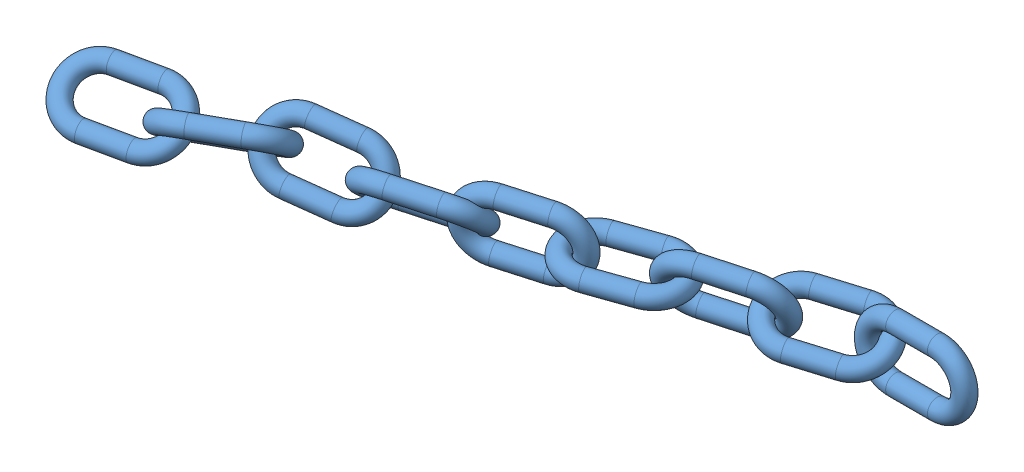
SolidWorks assembly chaine maillons soudés dia 6 L24 l 11, configuration Défaut. Lengths in mm.
Overall size (213.96 40.16 99.68).
9 component instances, 1 part files, 8 mates.
Components (placement in the parent):
- maillons chaine courte soudes dia 6 L 24 l 11-1: maillons chaine courte soudes dia 6 L 24 l 11 [Défaut] at (-85.1355 11.4536 0) size (36 23 6)
- maillons chaine courte soudes dia 6 L 24 l 11-2: maillons chaine courte soudes dia 6 L 24 l 11 [Défaut] at (-108.0656 12.5903 4.8209) x (0.910841 -0.094729 -0.401739) z (-0.25133 -0.899356 -0.357761) size (36 23 6)
- maillons chaine courte soudes dia 6 L 24 l 11-3: maillons chaine courte soudes dia 6 L 24 l 11 [Défaut] at (-129.9525 15.0549 14.3518) x (0.913068 -0.110651 -0.392508) z (0.320723 -0.399634 0.858737) size (36 23 6)
- maillons chaine courte soudes dia 6 L 24 l 11-4: maillons chaine courte soudes dia 6 L 24 l 11 [Défaut] at (-151.7983 17.2315 24.0328) x (0.907416 -0.07073 -0.414238) z (-0.094171 -0.99489 -0.036413) size (36 23 6)
- maillons chaine courte soudes dia 6 L 24 l 11-5: maillons chaine courte soudes dia 6 L 24 l 11 [Défaut] at (-173.6436 19.3198 33.7389) x (0.913025 -0.103295 -0.394608) z (-0.384982 0.10151 -0.917325) size (36 23 6)
- maillons chaine courte soudes dia 6 L 24 l 11-6: maillons chaine courte soudes dia 6 L 24 l 11 [Défaut] at (-195.5795 21.8383 43.1447) x (0.914964 -0.106578 -0.389207) z (0.191128 -0.734995 0.650579) size (36 23 6)
- maillons chaine courte soudes dia 6 L 24 l 11-7: maillons chaine courte soudes dia 6 L 24 l 11 [Défaut] at (-217.7164 25.3114 51.6491) x (0.929782 -0.182849 -0.319488) z (-0.367473 -0.40992 -0.834823) size (36 23 6)
- maillons chaine courte soudes dia 6 L 24 l 11-8: maillons chaine courte soudes dia 6 L 24 l 11 [Défaut] at (-239.2199 27.7106 61.5587) x (0.862177 -0.017087 -0.506319) z (0.298637 -0.790179 0.535195) size (36 23 6)
- maillons chaine courte soudes dia 6 L 24 l 11-9: maillons chaine courte soudes dia 6 L 24 l 11 [Défaut] at (-261.0732 28.6321 70.9618) x (0.958934 -0.059704 -0.277274) z (-0.21646 -0.785757 -0.579422) size (36 23 6)
Mates (geometry in assembly coordinates):
- Coïncidente1: coincident: point of maillons chaine courte soudes dia 6 L 24 l 11-1; point of maillons chaine courte soudes dia 6 L 24 l 11-2
- Coïncidente4: coincident: point of maillons chaine courte soudes dia 6 L 24 l 11-2; point of maillons chaine courte soudes dia 6 L 24 l 11-3
- Coïncidente5: coincident: point of maillons chaine courte soudes dia 6 L 24 l 11-3; point of maillons chaine courte soudes dia 6 L 24 l 11-4
- Coïncidente6: coincident: point of maillons chaine courte soudes dia 6 L 24 l 11-4; point of maillons chaine courte soudes dia 6 L 24 l 11-5
- Coïncidente7: coincident: point of maillons chaine courte soudes dia 6 L 24 l 11-5; point of maillons chaine courte soudes dia 6 L 24 l 11-6
- Coïncidente8: coincident: point of maillons chaine courte soudes dia 6 L 24 l 11-6; point of maillons chaine courte soudes dia 6 L 24 l 11-7
- Coïncidente9: coincident: point of maillons chaine courte soudes dia 6 L 24 l 11-7; point of maillons chaine courte soudes dia 6 L 24 l 11-8
- Coïncidente10: coincident: point of maillons chaine courte soudes dia 6 L 24 l 11-8; point of maillons chaine courte soudes dia 6 L 24 l 11-9
